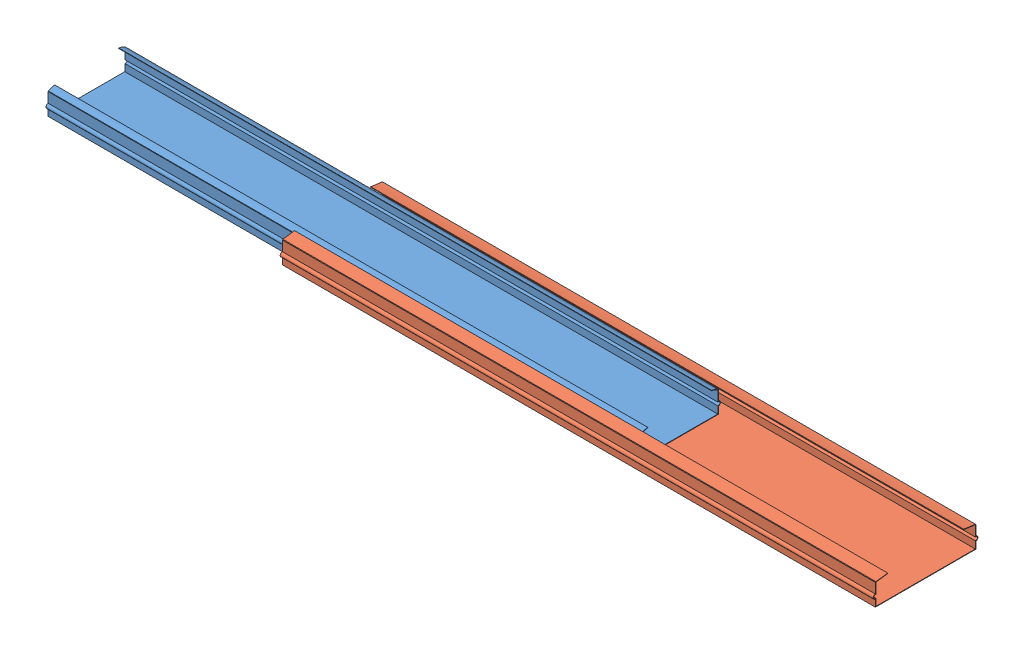
SolidWorks assembly slider, configuration Default. Lengths in mm.
Overall size (359 10.5 44.88).
2 component instances, 2 part files, 6 mates.
Components (placement in the parent):
- inner slider-1: inner slider [Default] at (-151.895 -7.559 16.8408) size (254 10.3 34.88)
- outer slider-1: outer slider [Default] at (-46.895 -7.759 16.5388) size (254 10.08 44.88)
Mates (geometry in assembly coordinates):
- Coincident3: coincident anti-aligned: plane of inner slider-1 through (-166.895 -7.559 16.8408) normal (0 -1 0); plane of outer slider-1 through (-46.895 -7.559 16.5388) normal (0 1 0)
- Parallel1: parallel aligned: line of inner slider-1 through (-45.9131 -7.359 33.1376) axis (0 0 -1); line of outer slider-1 through (74.0869 -7.559 37.8356) axis (0 0 -1)
- Parallel2: parallel aligned: axis of inner slider-1 through (-45.9131 -3.6141 33.3408) axis (-1 0 0); axis of outer slider-1 through (74.0869 -3.8141 38.0388) axis (-1 0 0)
- Parallel5: parallel: plane of inner slider-1 through (-166.895 -7.359 16.8408) normal (0 1 0); axis of outer slider-1 through (74.0869 -3.8141 -4.9612) axis (-1 0 0)
- Distance5: distance = 5.302 mm aligned: plane of outer slider-1 through (74.0869 -2.8748 -4.9612) normal (0 0 -1); plane of inner slider-1 through (-30.9131 -2.6748 0.3408) normal (0 0 -1)
- Distance6: distance = 105 mm aligned: plane of outer slider-1 through (-179.9131 -7.559 -4.9612) normal (-1 0 0); plane of inner slider-1 through (-284.9131 -7.359 0.3408) normal (-1 0 0)
